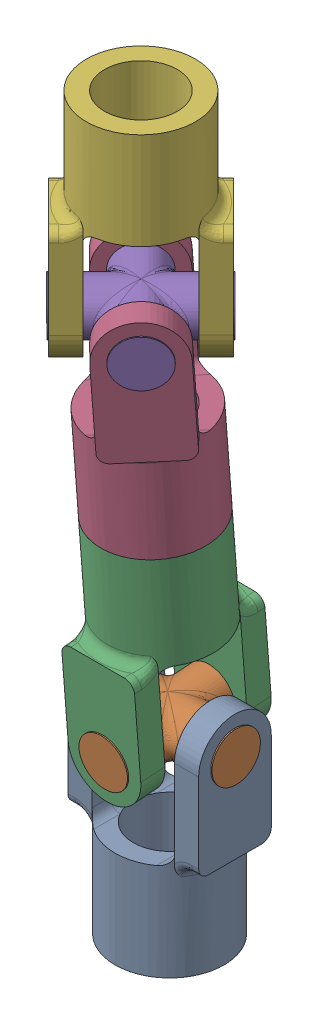
SolidWorks assembly 230020, configuration Default. Lengths in mm.
Overall size (49.84 195.29 50.84).
6 component instances, 2 part files, 11 mates.
Components (placement in the parent):
- 230018-1: 230018 [Default] at origin size (34.29 58.42 28.57)
- 230019-1: 230019 [Default] at (0 23.495 0) x (1 0 0) z (0 -0.076918 0.997037) size (34.92 12.7 34.92)
- 230018-2: 230018 [Default] at (0 46.9204 1.8072) x (0 -0.076918 0.997037) z (1 0 0) size (34.29 58.42 28.57)
- 230018-3: 230018 [Default] at (0 97.5699 5.7146) x (0.707107 -0.054389 0.705012) z (-0.707107 -0.054389 0.705012) size (34.29 58.42 28.57)
- 230019-2: 230019 [Default] at (0 120.9953 7.5218) x (0.706057 0 -0.708155) z (0.707107 -0.054389 0.705012) size (34.92 12.7 34.92)
- 230018-4: 230018 [Default] at (0 144.4903 7.5218) x (-0.706057 0 0.708155) z (0.708155 0 0.706057) size (34.29 58.42 28.57)
Mates (geometry in assembly coordinates):
- Concentric1: concentric anti-aligned: cylinder of U-Joint Housing-1 through (-17.145 23.495 0) axis (1 0 0) radius 6.35; cylinder of U-Joint Cross-1 through (17.4625 23.495 0) axis (-1 0 0) radius 6.35
- Width1: width anti-aligned: plane of U-Joint Cross-1 through (17.4625 23.495 0) normal (1 0 0); plane of U-Joint Housing-1 through (-17.4625 23.495 0) normal (-1 0 0); plane of U-Joint Cross-1 through (-17.145 0 9.525) normal (-1 0 0); plane of U-Joint Housing-1 through (17.145 0 9.525) normal (1 0 0)
- Concentric2: concentric anti-aligned: cylinder of U-Joint Cross-1 through (0 22.1518 17.4108) axis (0 0.076918 -0.997037) radius 6.35; cylinder of U-Joint Housing-2 through (0 24.8138 -17.0942) axis (0 -0.076918 0.997037) radius 6.35
- Width2: width anti-aligned: plane of U-Joint Cross-1 through (0 22.1518 17.4108) normal (0 -0.076918 0.997037); plane of U-Joint Housing-2 through (0 24.8382 -17.4108) normal (0 0.076918 -0.997037); plane of U-Joint Cross-1 through (9.525 46.0901 12.5702) normal (0 0.076918 -0.997037); plane of U-Joint Housing-2 through (9.525 47.7507 -8.9558) normal (0 -0.076918 0.997037)
- Concentric3: concentric anti-aligned: cylinder of U-Joint Housing-2 through (0 72.2451 3.7609) axis (0 -0.997037 -0.076918) radius 14.2875; cylinder of U-Joint Housing-3 through (0 72.2451 3.7609) axis (0 0.997037 0.076918) radius 14.2875
- Coincident2: coincident anti-aligned: plane of U-Joint Housing-2 through (0 72.2451 3.7609) normal (0 0.997037 0.076918); plane of U-Joint Housing-3 through (0 72.2451 3.7609) normal (0 -0.997037 -0.076918)
- Angle2: planar angle = 0.785398 rad anti-aligned: plane of U-Joint Housing-3 through (-18.8585 97.9843 0.3424) normal (-0.707107 0.054389 -0.705012); plane of U-Joint Housing-2 through (9.525 45.6016 18.9014) normal (0 -0.076918 0.997037)
- Concentric4: concentric anti-aligned: cylinder of U-Joint Housing-3 through (-12.1233 121.9278 -4.5656) axis (0.707107 -0.054389 0.705012) radius 6.35; cylinder of U-Joint Cross-2 through (12.3479 120.0455 19.8331) axis (-0.707107 0.054389 -0.705012) radius 6.35
- Width3: width anti-aligned: plane of U-Joint Cross-2 through (-12.3479 121.9451 -4.7894) normal (-0.707107 0.054389 -0.705012); plane of U-Joint Housing-3 through (12.3479 120.0455 19.8331) normal (0.707107 -0.054389 0.705012); plane of U-Joint Cross-2 through (5.3882 96.1193 24.5173) normal (0.707107 -0.054389 0.705012); plane of U-Joint Housing-3 through (-18.8585 97.9843 0.3424) normal (-0.707107 0.054389 -0.705012)
- Concentric5: concentric aligned: cylinder of U-Joint Cross-2 through (12.3295 120.9953 -4.8443) axis (-0.706057 0 0.708155) radius 6.35; cylinder of U-Joint Housing-4 through (12.1053 120.9953 -4.6195) axis (-0.706057 0 0.708155) radius 6.35
- Width4: width anti-aligned: plane of U-Joint Housing-4 through (-5.3602 144.4903 26.3883) normal (-0.706057 0 0.708155); plane of U-Joint Cross-2 through (18.8505 144.4903 2.1057) normal (0.706057 0 -0.708155); plane of U-Joint Housing-4 through (12.3295 120.9953 -4.8443) normal (0.706057 0 -0.708155); plane of U-Joint Cross-2 through (-12.3295 120.9953 19.888) normal (-0.706057 0 0.708155)
